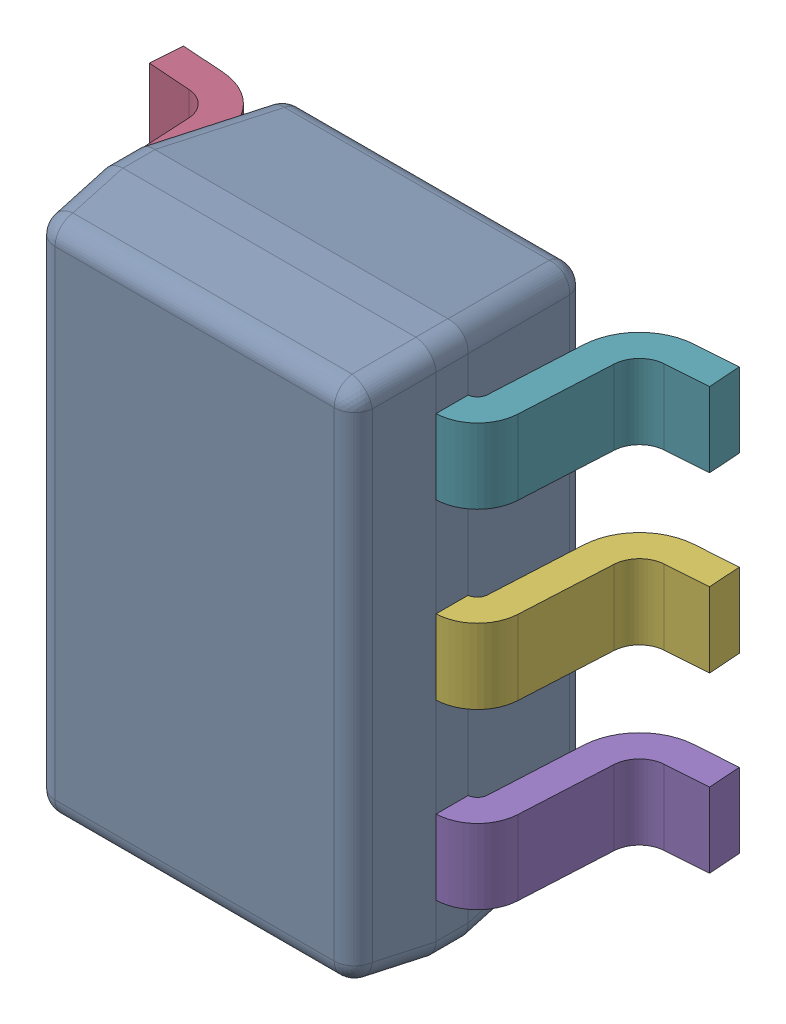
SolidWorks assembly IC9_2.step, configuration Default. Lengths in mm.
Overall size (2.1 2 1).
8 component instances, 2 part files, 0 mates.
Components (placement in the parent):
- 9655844400.step-1: 9655844400.step [Default] at (91.694 33.274 0) x (1 0 0) z (0 0 1) size (2.1 2 1)
  - BODY-SOT_2.step-8: BODY-SOT_2.step [Default] at (0 0 0.72) x (0 -1 0) z (-1 0 0) size (2 0.9 1.25)
  - LEAD-SOT_2.step-60: LEAD-SOT_2.step [Default] at (-0.6816 -0.65 0.15) x (0 -1 0) z (-1 0 0) size (0.28 0.72 0.43)
  - LEAD-SOT_2.step-61: LEAD-SOT_2.step [Default] at (-0.6816 0 0.15) x (0 -1 0) z (-1 0 0) size (0.28 0.72 0.43)
  - LEAD-SOT_2.step-62: LEAD-SOT_2.step [Default] at (-0.6816 0.65 0.15) x (0 -1 0) z (-1 0 0) size (0.28 0.72 0.43)
  - LEAD-SOT_2.step-63: LEAD-SOT_2.step [Default] at (0.6816 -0.65 0.15) x (0 1 0) z (1 0 0) size (0.28 0.72 0.43)
  - LEAD-SOT_2.step-64: LEAD-SOT_2.step [Default] at (0.6816 0 0.15) x (0 1 0) z (1 0 0) size (0.28 0.72 0.43)
  - LEAD-SOT_2.step-65: LEAD-SOT_2.step [Default] at (0.6816 0.65 0.15) x (0 1 0) z (1 0 0) size (0.28 0.72 0.43)
